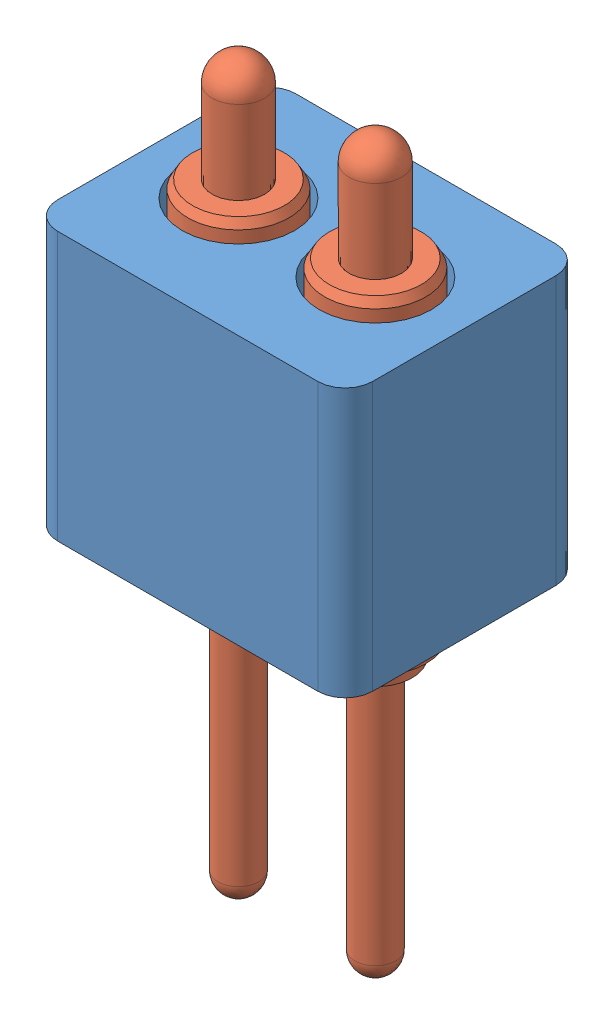
SolidWorks assembly mill-max-854-22-002-10-004101, configuration Default. Lengths in mm.
Overall size (2.92 6.76 2.21).
3 component instances, 2 part files, 0 mates.
Components (placement in the parent):
- mill-max-854-22-002-10-004101_P8XX-18-015-02-000000(P802-18-015-02-000000)-1: mill-max-854-22-002-10-004101_P8XX-18-015-02-000000(P802-18-015-02-000000) [Default] at origin size (2.92 2.49 2.21)
- mill-max-854-22-002-10-004101_0984-1: mill-max-854-22-002-10-004101_0984 [Default] at (2.0955 -2.7432 -1.1049) x (0 1 0) z (-0.857222 0 -0.514947) size (6.76 1.09 1.09)
- mill-max-854-22-002-10-004101_0984-2: mill-max-854-22-002-10-004101_0984 [Default] at (0.8255 -2.7432 -1.1049) x (0 1 0) z (-0.857222 0 -0.514947) size (6.76 1.09 1.09)
